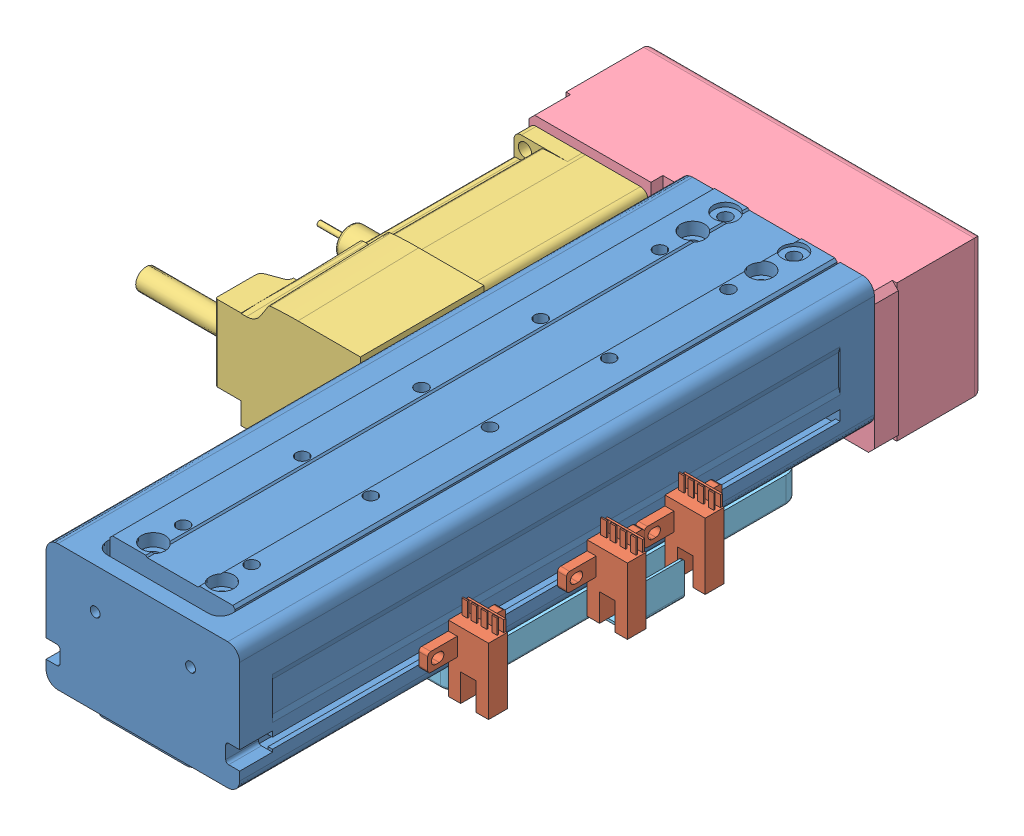
SolidWorks assembly S6M-BR-100W, configuration 默认. Lengths in mm.
Overall size (164.2 56 253.24).
7 component instances, 5 part files, 26 mates.
Components (placement in the parent):
- S6-BL滑块滑轨(CPC)BR-BL-BM共用^S6M-BR-100W-1: S6-BL滑块滑轨(CPC)BR-BL-BM共用^S6M-BR-100W [默认] x (-1 0 0) z (0 0 1) size (65 44.9 219.73) (virtual)
- 传感器^S6M-BR-100W-1: 传感器^S6M-BR-100W [默认] at (39.25 -39.2 135.7) size (13.5 27.2 26.1) (virtual)
- 传感器^S6M-BR-100W-2: 传感器^S6M-BR-100W [默认] at (39.25 -39.2 63) size (13.5 27.2 26.1) (virtual)
- 传感器^S6M-BR-100W-3: 传感器^S6M-BR-100W [默认] at (39.25 -39.2 89.1) size (13.5 27.2 26.1) (virtual)
- 复件 M10^S6M-BR-100W-1: 复件 M10^S6M-BR-100W [默认] at (-59.5 -28.9 59) x (0 -1 0) z (0 0 1) size (42.1 79.78 121.76) (virtual)
- S5-BL电机安装板^S6M-BR-100W-1: S5-BL电机安装板^S6M-BR-100W [默认] at (-23.5 -28.9 -1) x (1 0 0) z (0 0 -1) size (112 46 41) (virtual)
- S6-BC滑块组件^S6M-BR-100W-1: S6-BC滑块组件^S6M-BR-100W [Default] at (0 -1.5 161.7) x (1 0 0) z (0 1 0) size (69.5 116 25.18) (virtual)
Mates (geometry in assembly coordinates):
- 重合88: coincident: plane of 传感器^S6M-BR-100W-1 through (35.5 -37.4 125.8) normal (0 -1 0); plane of 传感器^S6M-BR-100W-2 through (35.5 -37.4 53.1) normal (0 -1 0)
- 重合92: coincident: plane of 传感器^S6M-BR-100W-2 through (35.5 -37.4 53.1) normal (0 -1 0); plane of 传感器^S6M-BR-100W-3 through (35.5 -37.4 79.2) normal (0 -1 0)
- 重合93: coincident: plane of 传感器^S6M-BR-100W-2 through (35.5 -31.3 79.2) normal (0 0 1); plane of 传感器^S6M-BR-100W-3 through (35.5 -31.3 79.2) normal (0 0 -1)
- 重合176: coincident: plane of 传感器^S6M-BR-100W-2 through (35.5 -31.3 79.2) normal (0 0 1); plane of 传感器^S6M-BR-100W-3 through (35.5 -31.3 79.2) normal (0 0 -1)
- 重合233: coincident: plane of S6-BC滑块组件^S6M-BR-100W-1; plane of assembly through (0 0 0) normal (1 0 0)
- 重合246: coincident: plane of 传感器^S6M-BR-100W-2 through (35.5 -37.4 53.1) normal (1 0 0); plane of 传感器^S6M-BR-100W-3 through (35.5 -37.4 79.2) normal (1 0 0)
- 距离1: distance = 56 mm: plane of S6-BC滑块组件^S6M-BR-100W-1 through (21 -56 99.2) normal (0 -1 0); plane of S6-BL滑块滑轨(CPC)BR-BL-BM共用^S6M-BR-100W-1 through (0 0 202) normal (0 1 0)
- 重合248: coincident: plane of 传感器^S6M-BR-100W-2 through (46 -50.3 69.3) normal (1 0 0); plane of 传感器^S6M-BR-100W-3 through (46 -50.3 95.4) normal (1 0 0)
- 重合249: coincident: plane of 传感器^S6M-BR-100W-1 through (46 -50.3 142) normal (1 0 0); plane of 传感器^S6M-BR-100W-3 through (46 -50.3 95.4) normal (1 0 0)
- 重合250: coincident: plane of 传感器^S6M-BR-100W-2 through (32.5 -28.1 69.3) normal (0 1 0); plane of 传感器^S6M-BR-100W-3 through (32.5 -28.1 95.4) normal (0 1 0)
- 重合251: coincident: plane of 传感器^S6M-BR-100W-1 through (32.5 -28.1 142) normal (0 1 0); plane of 传感器^S6M-BR-100W-3 through (32.5 -28.1 95.4) normal (0 1 0)
- 距离5: distance = 70 mm: plane of 传感器^S6M-BR-100W-1 through (46 -28.1 142) normal (0 0 1); plane of S6-BL滑块滑轨(CPC)BR-BL-BM共用^S6M-BR-100W-1 through (0 0 212) normal (0 0 1)
- 重合258: coincident: plane of S6-BL滑块滑轨(CPC)BR-BL-BM共用^S6M-BR-100W-1 through (32.5 -39.9 -67.1611) normal (1 0 0); plane of 传感器^S6M-BR-100W-1 through (32.5 -50.3 142) normal (-1 0 0)
- 距离7: distance = 28.1 mm: plane of 传感器^S6M-BR-100W-1 through (32.5 -28.1 142) normal (0 1 0); plane of S6-BL滑块滑轨(CPC)BR-BL-BM共用^S6M-BR-100W-1 through (0 0 202) normal (0 1 0)
- 重合260: coincident: plane of S6-BL滑块滑轨(CPC)BR-BL-BM共用^S6M-BR-100W-1; plane of S6-BC滑块组件^S6M-BR-100W-1
- 重合261: coincident: plane of S6-BL滑块滑轨(CPC)BR-BL-BM共用^S6M-BR-100W-1; plane of assembly through (0 0 0) normal (1 0 0)
- 重合262: coincident: plane of S6-BL滑块滑轨(CPC)BR-BL-BM共用^S6M-BR-100W-1; plane of assembly through (0 0 0) normal (0 1 0)
- 重合263: coincident: plane of S6-BL滑块滑轨(CPC)BR-BL-BM共用^S6M-BR-100W-1 through (0 0 0) normal (0 0 1); plane of assembly through (0 0 0) normal (0 0 1)
- 重合264: coincident: plane of S6-BL滑块滑轨(CPC)BR-BL-BM共用^S6M-BR-100W-1 through (32.5 -39.9 -67.1611) normal (1 0 0); plane of S5-BL电机安装板^S6M-BR-100W-1 through (32.5 -5.9 -9) normal (1 0 0)
- 重合265: coincident: plane of S6-BL滑块滑轨(CPC)BR-BL-BM共用^S6M-BR-100W-1 through (0 0 -1) normal (0 0 -1); plane of S5-BL电机安装板^S6M-BR-100W-1 through (32.5 -51.9 -1) normal (0 0 1)
- 重合267: coincident: plane of 复件 M10^S6M-BR-100W-1 through (-60.9978 -106.8984 3) normal (0 0 -1); plane of S5-BL电机安装板^S6M-BR-100W-1 through (-23.5 -28.9 3) normal (0 0 1)
- 同心1: concentric: cylinder of 复件 M10^S6M-BR-100W-1 through (-59.5 -28.9 -22) axis (0 0 1) radius 4; cylinder of S5-BL电机安装板^S6M-BR-100W-1 through (-59.5 -28.9 3) axis (0 0 -1) radius 15.1
- 平行1: parallel: plane of 复件 M10^S6M-BR-100W-1 through (-79.5 -28.9 59) normal (-1 0 0); plane of S5-BL电机安装板^S6M-BR-100W-1 through (-79.5 -5.9 -9) normal (-1 0 0)
- 距离9: distance = 8 mm: plane of S5-BL电机安装板^S6M-BR-100W-1 through (-79.5 -51.9 -9) normal (0 -1 0); plane of S6-BL滑块滑轨(CPC)BR-BL-BM共用^S6M-BR-100W-1 through (0 -43.9 -67.1611) normal (0 -1 0)
- 距离10: distance = 101 mm: plane of 传感器^S6M-BR-100W-2 through (46 -28.1 63) normal (0 0 -1); plane of S5-BL电机安装板^S6M-BR-100W-1 through (-23.5 -28.9 -38) normal (0 0 -1)
- 宽度1: width: plane of 传感器^S6M-BR-100W-2 through (46 -28.1 69.3) normal (0 0 1); plane of 传感器^S6M-BR-100W-3 through (46 -28.1 89.1) normal (0 0 -1); plane of S6-BC滑块组件^S6M-BR-100W-1 through (28.75 -49.4 69.7) normal (0 0 -1); plane of S6-BC滑块组件^S6M-BR-100W-1 through (28.75 -49.4 88.7) normal (0 0 1)
